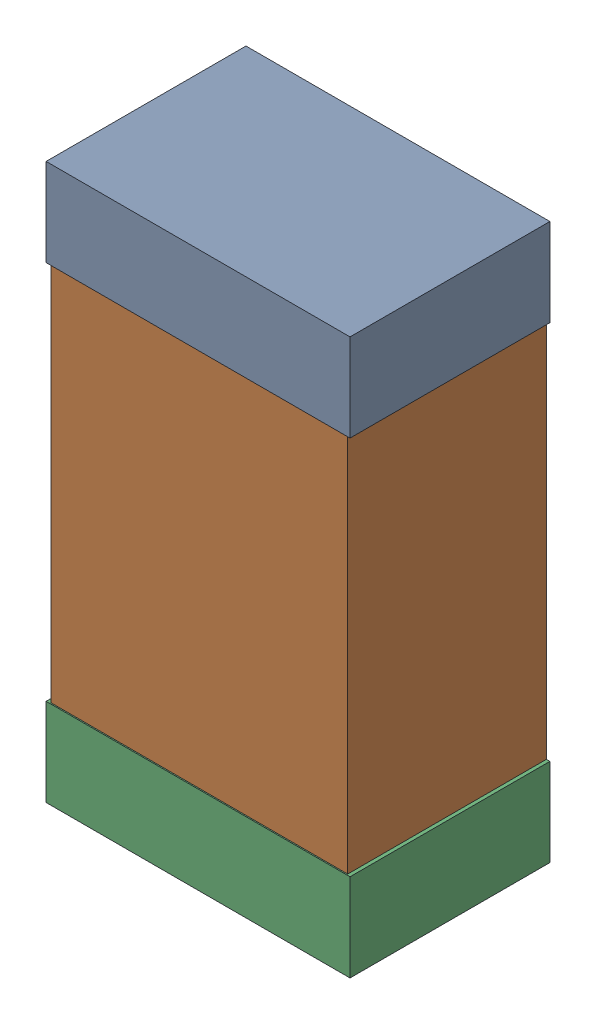
SolidWorks assembly C9Kanaloa_v2.0.0_Power, configuration Default. Lengths in mm.
Overall size (1.3 2.38 0.85).
6 component instances, 2 part files, 0 mates.
Components (placement in the parent):
- 330415056-1: 330415056 [Default] at (64.475 94 0) size (1.3 0.38 0.85)
  - Extruded_2-1: Extruded_2 [Default] at origin size (1.3 0.38 0.85)
- 352877008-1: 352877008 [Default] at (64.475 93 0) size (1.27 2.2 0.85)
  - Extruded_3-1: Extruded_3 [Default] at origin size (1.27 2.2 0.85)
- 330415056-2: 330415056 [Default] at (64.475 92 0) size (1.3 0.38 0.85)
  - Extruded_2-1: Extruded_2 [Default] at origin size (1.3 0.38 0.85)
